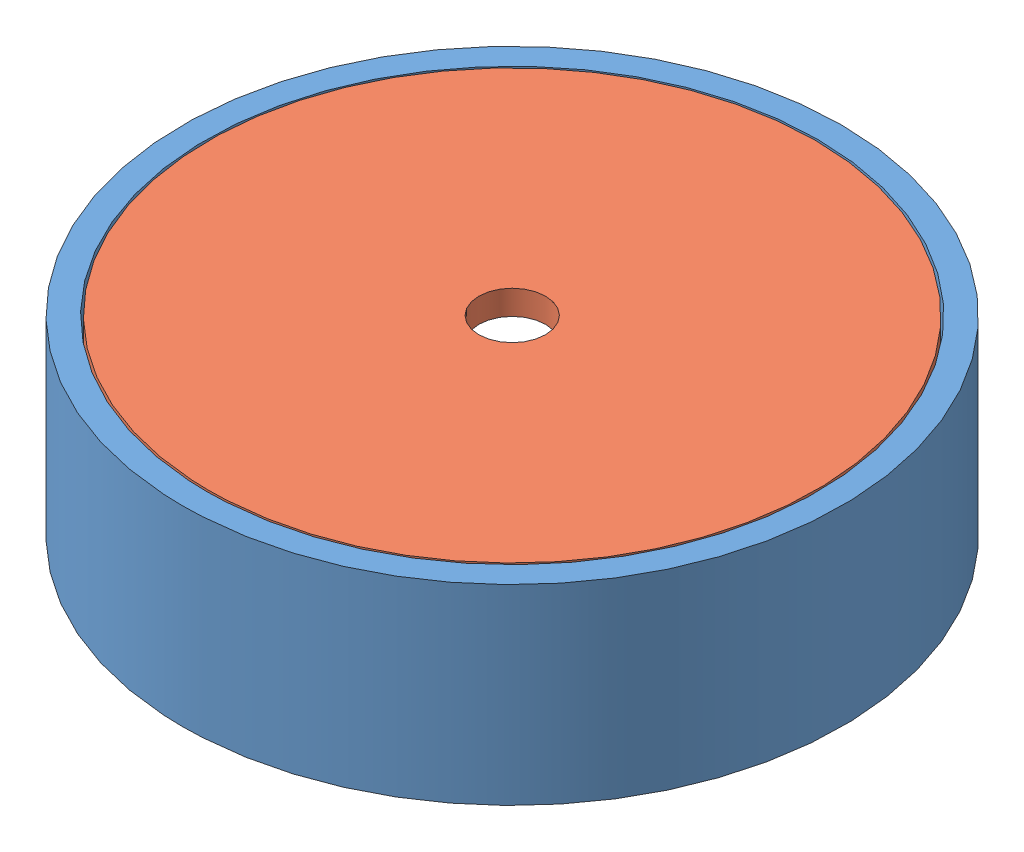
SolidWorks assembly base, configuration Default. Lengths in mm.
Overall size (81 23.5 81).
2 component instances, 2 part files, 2 mates.
Components (placement in the parent):
- baseRing-1: baseRing [Default] at (23.6099 36.609 61.5339) size (81 23.5 81)
- baseCover-1: baseCover [Default] at (23.6099 57.109 61.5339) size (75 3 75)
Mates (geometry in assembly coordinates):
- Coincident1: coincident aligned: plane of baseRing-1 through (23.6099 60.109 61.5339) normal (0 1 0); plane of baseCover-1 through (23.6099 60.109 61.5339) normal (0 1 0)
- Concentric1: concentric anti-aligned: cylinder of baseRing-1 through (23.6099 60.109 61.5339) axis (0 -1 0) radius 37.5; circle of baseCover-1
